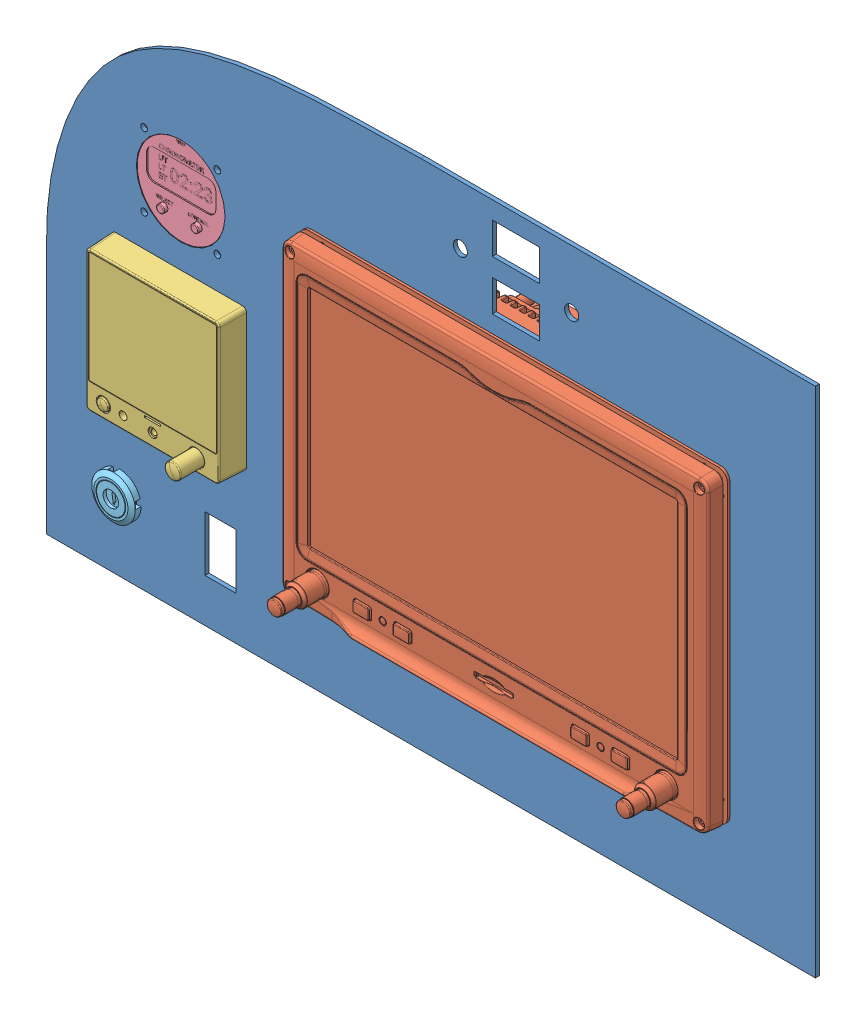
SolidWorks assembly Assem1, configuration Default. Lengths in mm.
Overall size (554.47 367.87 140.02).
6 component instances, 5 part files, 34 mates.
Components (placement in the parent):
- GDU46X_010-01057-(00,10)_H[010-12150-00]_rev2.step-1: GDU46X_010-01057-(00,10)_H[010-12150-00]_rev2.step [Default] at (278.2015 -97.4153 137.7241) x (-0.00118 0.00565 -0.999983) z (0.999999 -0.001157 -0.001187) size (275.52 198.62 129.5) (hidden)
- Glasair Panel-2: Glasair Panel [Default] at (-158.083 -74.8231 1106.7991) size (495.89 338.28 2.54)
- GDU46X_010-01057-(00,10)_H[010-12150-00]_rev2.step-3: GDU46X_010-01057-(00,10)_H[010-12150-00]_rev2.step [Default] at (-75.5992 -30.3775 1114.0666) size (275.52 198.62 129.5)
- Garmin-G5-PFD.stp-1: Garmin-G5-PFD.stp [Default] at (-292.7415 -41.6704 1109.3391) x (0 0 1) z (0 1 0) size (82.42 137.58 110.44)
- Davtron M800 Chronometer.step-1: Davtron M800 Chronometer.step [Default] at (-291.4398 48.4744 1106.7991) size (60.32 60.32 25.4)
- ignition switch.ipt-1: ignition switch.ipt [Default] at (-331.1691 -140.8463 1106.8034) x (0 0 -1) z (0.988895 0.148613 0) size (57.3 31 31)
Mates (geometry in assembly coordinates):
- Tangent3: tangent anti-aligned: plane of ? through (273.9068 52.0851 356.6142) normal (0.999999 -0.001157 -0.001187); face of ?
- Tangent5: tangent aligned: plane of ? through (273.9068 52.0851 356.6142) normal (0.999999 -0.001157 -0.001187); edge_curve of ?
- Coincident4: coincident anti-aligned: plane of Glasair Panel-1 through (273.9068 52.0851 356.6142) normal (0.999999 -0.001157 -0.001187); plane of ignition switch.ipt-1 through (-331.1932 -140.6857 1109.3391) normal (0 0 -1)
- Coincident6: coincident anti-aligned: plane of Glasair Panel-1 through (273.9068 52.0851 356.6142) normal (0.999999 -0.001157 -0.001187); plane of Press to Test-2 through (43.5706 250.7058 337.7352) normal (-0.003905 -0.004282 -0.999983)
- Coincident8: coincident anti-aligned: plane of Glasair Panel-1 through (273.9068 52.0851 356.6142) normal (0.999999 -0.001157 -0.001187); plane of Press to Test-1 through (81.6927 250.941 337.5853) normal (-0.003905 -0.004282 -0.999983)
- Tangent14: tangent aligned: plane of ? through (205.3546 -214.8638 -110.9738) normal (0.999999 -0.001157 -0.001187); edge_curve of ?
- Tangent15: tangent aligned: cylinder of ? through (205.4339 -36.004 -218.5323) axis (-0.999999 0.001157 0.001187) radius 1.905; edge_curve of ?
- Tangent16: tangent aligned: cylinder of ? through (205.4339 -36.004 -218.5323) axis (-0.999999 0.001157 0.001187) radius 1.905; edge_curve of ?
- Parallel1: parallel aligned: line of Glasair Panel-1 through (273.0505 -254.81 -65.6194) axis (0.001162 0.99999 0.004277); line of Right Panel-1 through (202.6345 -271.7634 -207.2443) axis (0.001162 0.99999 0.004277)
- Coincident22: coincident: point of Panel-1; point of Dynon Panel Stack]^Assem1-1
- Coincident24: coincident anti-aligned: line of Right Panel-1 through (205.1745 -271.7663 -207.2473) axis (0.001162 0.99999 0.004277); line of Dynon Panel Stack]^Assem1-1 through (414.6636 131.5232 355.9437) axis (0.001162 -0.99999 0.004277)
- Coincident25: coincident anti-aligned: plane of Right Panel-1 through (205.2411 -214.4529 -207.0022) normal (0.001182 -0.004279 0.99999); plane of SM Part Panels-1 through (202.6554 -253.7954 -207.1675) normal (-0.001182 0.004279 -0.99999)
- Coincident26: coincident anti-aligned: plane of Glasair Panel-1 through (273.0505 -254.81 -65.6194) normal (-0.001182 0.004279 -0.99999); plane of SM Part Panels-1 through (202.8505 -254.5018 -42.0691) normal (0.001182 -0.004279 0.99999)
- Parallel4: parallel aligned: plane of Glasair Panel-1 through (273.9068 52.0851 356.6142) normal (0.999999 -0.001157 -0.001187); plane of SM Part Panels-1 through (205.5998 -255.2625 135.0364) normal (0.999999 -0.001157 -0.001187)
- Parallel5: parallel aligned: plane of Right Panel-1 through (205.3546 -214.8638 -110.9738) normal (0.999999 -0.001157 -0.001187); plane of SM Part Panels-1 through (205.5998 -255.2625 135.0364) normal (0.999999 -0.001157 -0.001187)
- Coincident32: coincident aligned: plane of Right Panel-1 through (205.3546 -214.8638 -110.9738) normal (0.999999 -0.001157 -0.001187); plane of SM Part Panels-1 through (205.5998 -255.2625 135.0364) normal (0.999999 -0.001157 -0.001187)
- Coincident33: coincident aligned: plane of Glasair Panel-1 through (273.9068 52.0851 356.6142) normal (0.999999 -0.001157 -0.001187); plane of SM Part Panels-1 through (205.5998 -255.2625 135.0364) normal (0.999999 -0.001157 -0.001187)
- Coincident36: coincident aligned: plane of Panel-1 through (205.6357 -228.1062 138.803) normal (-0.001162 -0.99999 -0.004277); plane of SM Part Panels-1 through (-161.0554 -227.6663 135.5879) normal (-0.001162 -0.99999 -0.004277)
- Tangent17: tangent anti-aligned: plane of ? through (273.9068 52.0851 356.6142) normal (0.999999 -0.001157 -0.001187); edge_curve of ?
- Tangent19: tangent anti-aligned: plane of ? through (273.9068 52.0851 356.6142) normal (0.999999 -0.001157 -0.001187); edge_curve of ?
- Tangent20: tangent anti-aligned: plane of ? through (273.9068 52.0851 356.6142) normal (0.999999 -0.001157 -0.001187); edge_curve of ?
- Tangent21: tangent aligned: plane of ? through (273.9068 52.0851 356.6142) normal (0.999999 -0.001157 -0.001187); edge_curve of ?
- Coincident46: coincident anti-aligned: plane of Glasair Panel-1 through (273.9068 52.0851 356.6142) normal (0.999999 -0.001157 -0.001187); plane of GDU46X_010-01057-(00,10)_H[010-12150-00]_rev2.step-1 through (273.1959 -195.9299 -0.5789) normal (-0.999999 0.001157 0.001187)
- Concentric4: concentric anti-aligned: circle of Glasair Panel-2; circle of GDU46X_010-01057-(00,10)_H[010-12150-00]_rev2.step-3
- Coincident47: coincident anti-aligned: plane of GDU46X_010-01057-(00,10)_H[010-12150-00]_rev2.step-3 through (62.1508 -129.6775 1109.3391) normal (0 0 -1); plane of Glasair Panel-2 through (-304.6472 121.3627 1109.3391) normal (0 0 1)
- Parallel14: parallel anti-aligned: line of Glasair Panel-2 through (117.2608 -186.4825 1109.3391) axis (0 1 0)
- Parallel15: parallel aligned: line of Glasair Panel-2 through (-378.0392 -186.4825 1109.3391) axis (1 0 0)
- Coincident50: coincident: unknown of Glasair Panel-2
- Coincident51: coincident anti-aligned: plane of Glasair Panel-2 through (-304.6472 121.3627 1109.3391) normal (0 0 1); plane of Garmin-G5-PFD.stp-1 through (-344.9223 -96.5944 1109.3391) normal (0 0 -1)
- Lock1: lock: unknown of Glasair Panel-2; unknown of Garmin-G5-PFD.stp-1
- Concentric5: concentric anti-aligned: circle of Glasair Panel-2; circle of ignition switch.ipt-1
- Coincident53: coincident anti-aligned: plane of Glasair Panel-2 through (-304.6472 121.3627 1109.3391) normal (0 0 1); plane of ignition switch.ipt-1 through (-331.1932 -140.6857 1109.3391) normal (0 0 -1)
- Coincident54: coincident anti-aligned: plane of Glasair Panel-2 through (-304.6472 121.3627 1106.7991) normal (0 0 -1); plane of Davtron M800 Chronometer.step-1 through (-291.4398 48.4744 1106.7991) normal (0 0 1)
- Concentric6: concentric anti-aligned: circle of Glasair Panel-2; circle of Davtron M800 Chronometer.step-1
